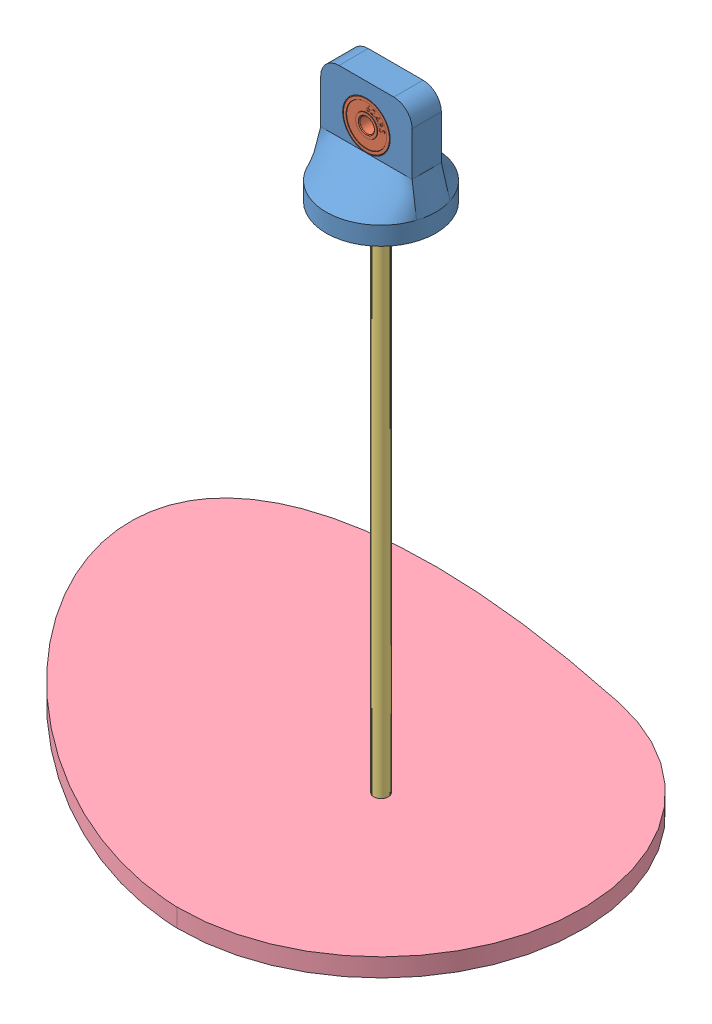
SolidWorks assembly legs, configuration Default. Lengths in mm.
Overall size (189.45 175.5 148.14).
5 component instances, 4 part files, 7 mates.
Components (placement in the parent):
- double-bearing-1: double-bearing [Default] at (12.9899 7.13 27.047) x (0 1 0) z (1 0 0) size (30.5 30.1 30.39)
- 624RS-1: 624RS [Default] at (12.9899 22.13 26.047) size (13 13 5)
- 624RS-2: 624RS [Default] at (12.9899 2.13 27.047) x (1 0 0) z (0 1 0) size (13 13 5)
- shell-spoke-1: shell-spoke [Default] at (12.9899 -92.87 27.047) x (-0.999501 0 -0.031598) z (0 1 0) size (4 4 150)
- shell-mockup-1: shell-mockup [Default] at (12.9899 -142.87 27.047) x (0.200645 0 -0.979664) z (0 1 0) size (116.49 169.53 5)
Mates (geometry in assembly coordinates):
- Concentric1: concentric aligned: cylinder of double-bearing-1 through (12.9899 22.13 31.047) axis (0 0 -1) radius 6.5; cylinder of 624RS-1 through (12.9899 22.13 31.047) axis (0 0 -1) radius 6.5
- Coincident1: coincident aligned: plane of double-bearing-1 through (25.4899 32.63 31.047) normal (0 0 1); plane of 624RS-1 through (12.9899 22.13 31.047) normal (0 0 1)
- Concentric2: concentric anti-aligned: cylinder of double-bearing-1 through (12.9899 2.13 27.047) axis (0 1 0) radius 6.5; cylinder of 624RS-2 through (12.9899 7.13 27.047) axis (0 -1 0) radius 6.5
- Coincident2: coincident aligned: plane of double-bearing-1 through (12.9899 2.13 27.047) normal (0 -1 0); plane of 624RS-2 through (12.9899 2.13 27.047) normal (0 -1 0)
- Concentric3: concentric anti-aligned: cylinder of 624RS-2 through (12.9899 7.13 27.047) axis (0 -1 0) radius 2; cylinder of shell-spoke-1 through (12.9899 -142.87 27.047) axis (0 1 0) radius 2
- Coincident3: coincident anti-aligned: plane of double-bearing-1 through (12.9899 7.13 27.047) normal (0 -1 0); plane of shell-spoke-1 through (12.9899 7.13 27.047) normal (0 1 0)
- Coincident5: coincident aligned: circle of shell-spoke-1; circle of shell-mockup-1
